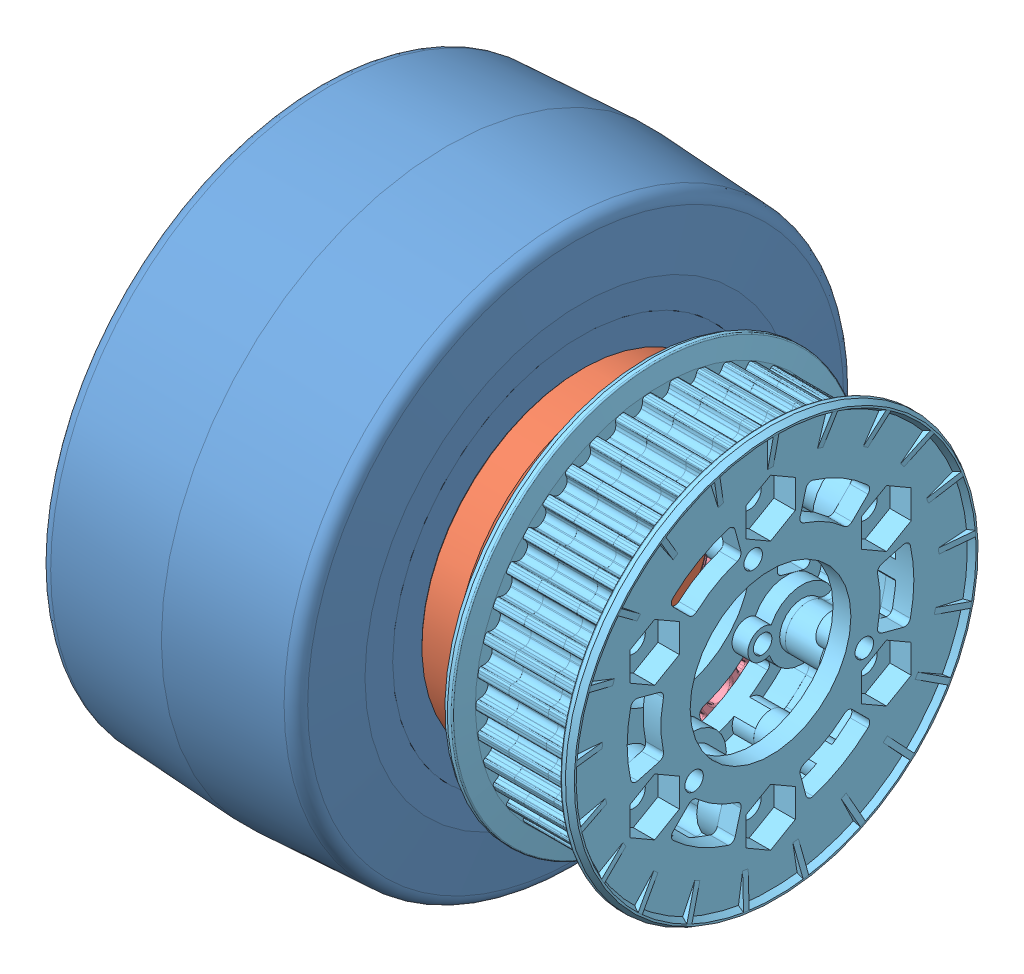
SolidWorks assembly wheel dead axis, configuration Default. Lengths in mm.
Overall size (87.16 101.6 101.6).
7 component instances, 6 part files, 12 mates.
Components (placement in the parent):
- colson wheel-1: colson wheel [Default] at (34.5983 59.2472 75.5116) size (47.77 101.6 101.6)
- hub dead axis-1: hub dead axis [Default] at (61.6576 59.2472 75.5116) x (0 0.55376 0.832676) z (-1 0 0) size (57.15 57.15 47.62)
- bearing-1: bearing [Default] at (57.6889 59.2472 75.5116) size (7.14 22.23 22.23)
- bearing-2: bearing [Default] at (17.2074 59.2472 75.5116) size (7.14 22.23 22.23)
- versahub 1.125 in bearing pilot-1: versahub 1.125 in bearing pilot [Default] at (68.0076 59.2472 75.5116) x (0 1 0) z (0 0 1) size (55.88 12.7 55.88)
- pulley-1: pulley [Default] at (90.5951 59.2472 75.5116) x (0 0 -1) z (1 0 0) size (73 73 23.01)
- spacer for dead axis-2: spacer for dead axis [Default] at (6.0316 59.2472 75.5116) x (0 0.370269 -0.928924) z (1 0 0) size (30.04 30.04 11.18)
Mates (geometry in assembly coordinates):
- Concentric1: concentric anti-aligned: cylinder of colson wheel-1 through (-37.9732 59.2472 75.5116) axis (-1 0 0) radius 15.1257; cylinder of hub dead axis-1 through (17.2076 59.2472 75.5116) axis (1 0 0) radius 15.24
- Coincident1: coincident anti-aligned: plane of colson wheel-1 through (58.4826 118.1679 -0.6884) normal (1 0 0); plane of hub dead axis-1 through (58.4826 75.0709 99.3053) normal (-1 0 0)
- Coincident2: coincident anti-aligned: plane of hub dead axis-1 through (57.6889 65.3938 84.7541) normal (1 0 0); plane of bearing-1 through (57.6889 64.4102 75.5116) normal (-1 0 0)
- Concentric2: concentric anti-aligned: cylinder of hub dead axis-1 through (17.2076 59.2472 75.5116) axis (1 0 0) radius 11.0998; cylinder of bearing-1 through (64.8366 59.2472 75.5116) axis (-1 0 0) radius 11.113
- Coincident3: coincident anti-aligned: plane of hub dead axis-1 through (24.3514 64.5217 83.4428) normal (-1 0 0); plane of bearing-2 through (24.3514 65.6142 75.5116) normal (1 0 0)
- Concentric3: concentric anti-aligned: cylinder of hub dead axis-1 through (17.2076 59.2472 75.5116) axis (1 0 0) radius 11.0998; cylinder of bearing-2 through (24.3551 59.2472 75.5116) axis (-1 0 0) radius 11.113
- Coincident4: coincident anti-aligned: plane of hub dead axis-1 through (64.8326 59.2472 75.5116) normal (1 0 0); plane of versahub 1.125 in bearing pilot-1 through (64.8326 59.2472 75.5116) normal (-1 0 0)
- Concentric4: concentric aligned: cylinder of hub dead axis-1 through (58.4826 59.2472 75.5116) axis (1 0 0) radius 25.5; cylinder of versahub 1.125 in bearing pilot-1 through (61.6576 59.2472 75.5116) axis (1 0 0) radius 25.5
- Coincident5: coincident anti-aligned: plane of versahub 1.125 in bearing pilot-1 through (71.1826 59.2472 75.5116) normal (1 0 0); plane of pulley-1 through (71.1826 59.2472 75.5116) normal (-1 0 0)
- Concentric5: concentric aligned: cylinder of versahub 1.125 in bearing pilot-1 through (74.3576 59.2472 75.5116) axis (-1 0 0) radius 25.5; cylinder of pulley-1 through (81.1826 59.2472 75.5116) axis (-1 0 0) radius 25.5
- Concentric6: concentric aligned: cylinder of colson wheel-1 through (-37.9732 59.2472 75.5116) axis (-1 0 0) radius 15.1257; cylinder of spacer for dead axis-2 through (17.2076 59.2472 75.5116) axis (-1 0 0) radius 15.0177
- Coincident8: coincident anti-aligned: plane of hub dead axis-1 through (17.2076 59.2472 75.5116) normal (-1 0 0); plane of spacer for dead axis-2 through (17.2076 59.2472 75.5116) normal (1 0 0)
